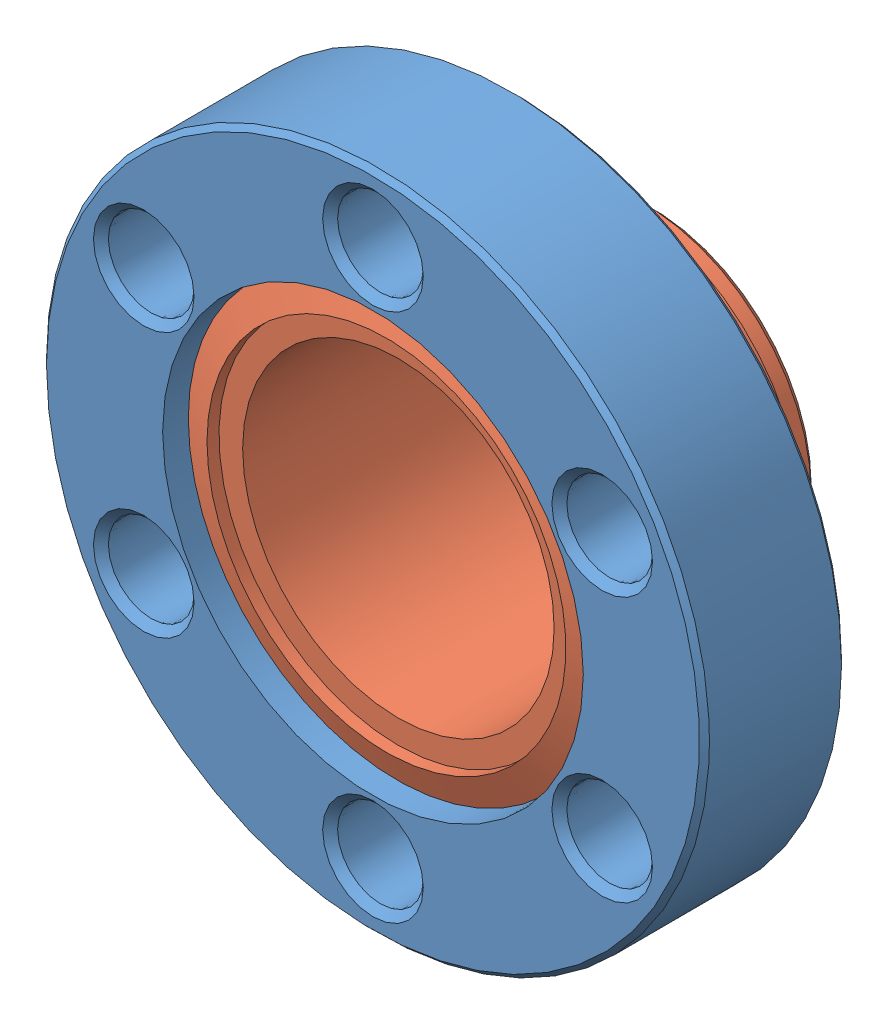
SolidWorks assembly 100004_ASM, configuration Default. Lengths in mm.
Overall size (33.78 33.78 14.2).
2 component instances, 2 part files, 0 mates.
Components (placement in the parent):
- 915000-1: 915000 [Default] at origin size (33.78 33.78 7.24)
- MINI_INSERT-1: MINI_INSERT [Default] at (0 0 -5.842) x (-1 0 0) z (0 1 0) size (21.29 13.51 21.29)
